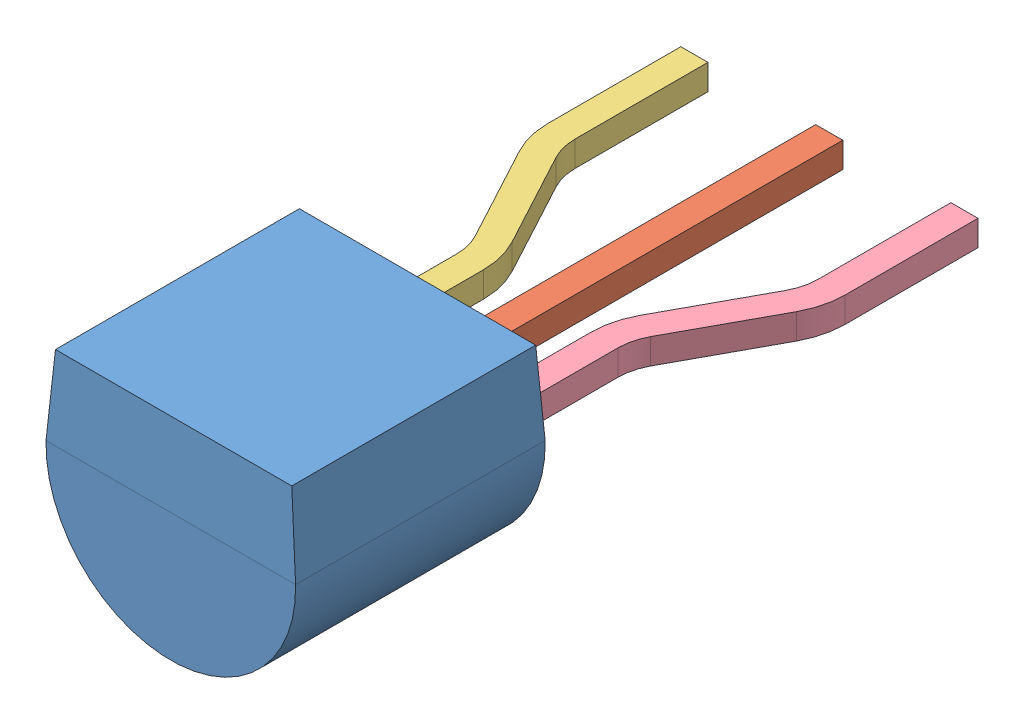
SolidWorks assembly User Library-TO-92-2.54-line-1, configuration Default. Lengths in mm.
Overall size (5.6 3.93 12.4).
4 component instances, 4 part files, 0 mates.
Components (placement in the parent):
- User Library-TO-92-2.54-line-1_User Library-TO-92 Version2_TO-92 Part1-1: User Library-TO-92-2.54-line-1_User Library-TO-92 Version2_TO-92 Part1 [Default] at origin size (4.7 3.93 4.7)
- User Library-TO-92-2.54-line-1_User Library-TO-92 Version2_TO-92 Part3-1: User Library-TO-92-2.54-line-1_User Library-TO-92 Version2_TO-92 Part3 [Default] at (2.35 -0.24 1) size (0.51 0.48 8.7)
- User Library-TO-92-2.54-line-1_User Library-TO-92 Version2_TO-92 Part4-1: User Library-TO-92-2.54-line-1_User Library-TO-92 Version2_TO-92 Part4 [Default] at (-4.32 -0.24 1) x (-1 0 0) z (0 0 1) size (1.78 0.48 8.7)
- User Library-TO-92-2.54-line-1_User Library-TO-92 Version2_TO-92 Part5-1: User Library-TO-92-2.54-line-1_User Library-TO-92 Version2_TO-92 Part5 [Default] at (-1.78 -0.24 1) x (-1 0 0) z (0 0 1) size (1.79 0.48 8.7)
